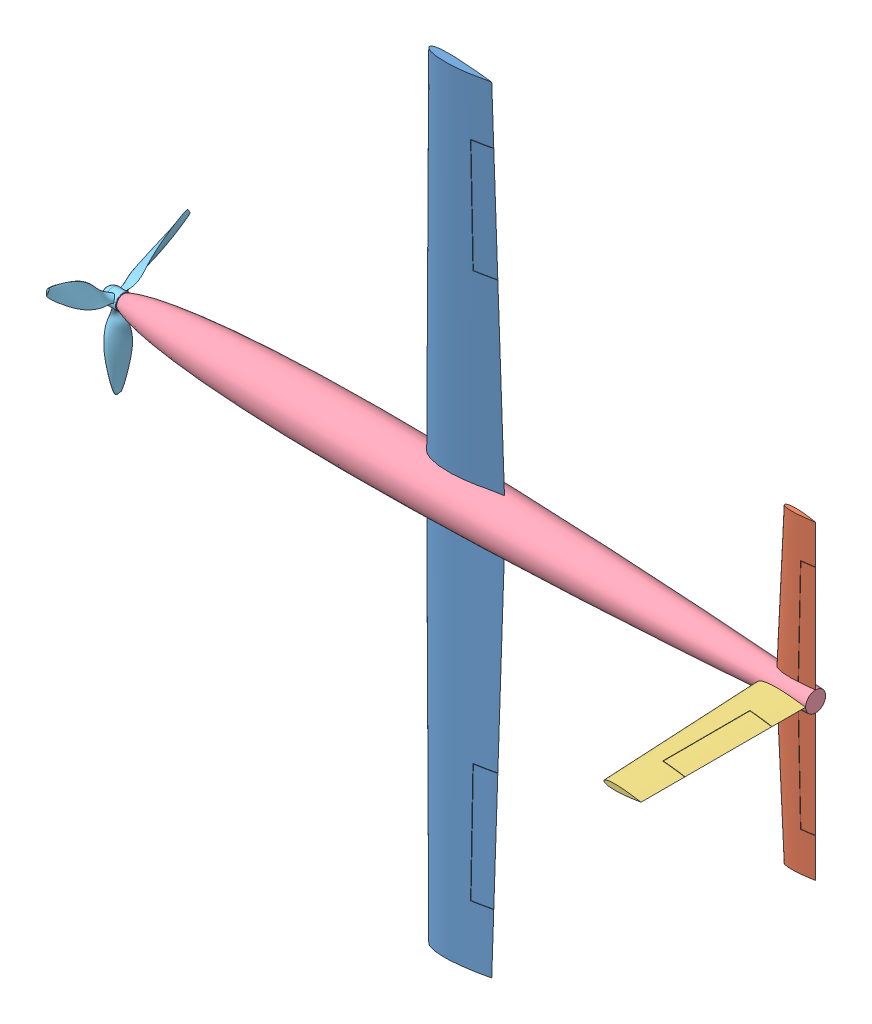
SolidWorks assembly kiteAssemblyWithProp_FS, configuration Default. Lengths in mm.
Overall size (9155.01 10000.08 3178.23).
5 component instances, 5 part files, 14 mates.
Components (placement in the parent):
- wing_FS-1: wing_FS [Default] x (1 0 0) z (0 0 -1) size (1000.26 10000.08 307.21)
- hStab_FS-1: hStab_FS [Default] at (4500 0 0) size (500.02 4000.02 75.08)
- vStab_FS-1: vStab_FS [Default] at (4400 0 0) x (1 0 0) z (0 -1 0) size (600.01 2250.01 90.12)
- fuselageWithProp_FS-1: fuselageWithProp_FS [Default] at (-4020 0 0) size (8920 660.77 660.77)
- propellerGrabCad-1: propellerGrabCad [Varsayılan] at (-3990 -75 0) x (0 -1 0) z (0 0 -1) size (1627.78 263.34 1860.42)
Mates (geometry in assembly coordinates):
- Distance2: distance = 0 mm: plane of assembly through (0 0 0) normal (0 0 1); plane of assembly; plane of wing_FS-1 through (0 0 0) normal (0 0 -1)
- Distance3: distance = 0 mm: plane of assembly through (0 0 0) normal (0 1 0); plane of assembly; plane of wing_FS-1 through (0 0 0) normal (0 -1 0)
- Distance4: distance = 0 mm: plane of assembly through (0 0 0) normal (1 0 0); plane of assembly; plane of wing_FS-1 through (0 0 0) normal (1 0 0)
- Distance5: distance = 0 mm anti-aligned: plane of wing_FS-1 through (0 0 0) normal (0 0 -1); plane of fuselageWithProp_FS-1 through (-4020 0 0) normal (0 0 1)
- Distance6: distance = 0 mm anti-aligned: plane of wing_FS-1 through (0 0 0) normal (0 -1 0); plane of fuselageWithProp_FS-1 through (-4020 0 0) normal (0 1 0)
- Distance7: distance = 0 mm anti-aligned: plane of hStab_FS-1 through (4500 0 0) normal (0 0 1); plane of wing_FS-1 through (0 0 0) normal (0 0 -1)
- Distance8: distance = 0 mm anti-aligned: plane of wing_FS-1 through (0 0 0) normal (0 -1 0); plane of hStab_FS-1 through (4500 0 0) normal (0 1 0)
- Distance9: distance = 0 mm aligned: plane of hStab_FS-1 through (5000 0 0) normal (1 0 0); plane of fuselageWithProp_FS-1 through (5000 0 0) normal (1 0 0)
- Distance10: distance = 0 mm aligned: plane of vStab_FS-1 through (4400 0 0) normal (0 -1 0); plane of wing_FS-1 through (0 0 0) normal (0 -1 0)
- Distance11: distance = 0 mm anti-aligned: plane of wing_FS-1 through (0 0 0) normal (0 0 -1); plane of vStab_FS-1 through (4400 0 0) normal (0 0 1)
- Distance12: distance = 0 mm aligned: plane of vStab_FS-1 through (5000 0 0) normal (1 0 0); plane of fuselageWithProp_FS-1 through (5000 0 0) normal (1 0 0)
- Distance14: distance = 0 mm aligned: plane of hStab_FS-1 through (4500 0 0) normal (1 0 0)
- Concentric1: concentric anti-aligned: circle of fuselageWithProp_FS-1; cylinder of propellerGrabCad-1 through (-3920 0 0) axis (-1 0 0) radius 100
- Coincident2: coincident anti-aligned: plane of fuselageWithProp_FS-1 through (-3920 0 0) normal (-1 0 0); plane of propellerGrabCad-1 through (-3920 0 0) normal (1 0 0)
